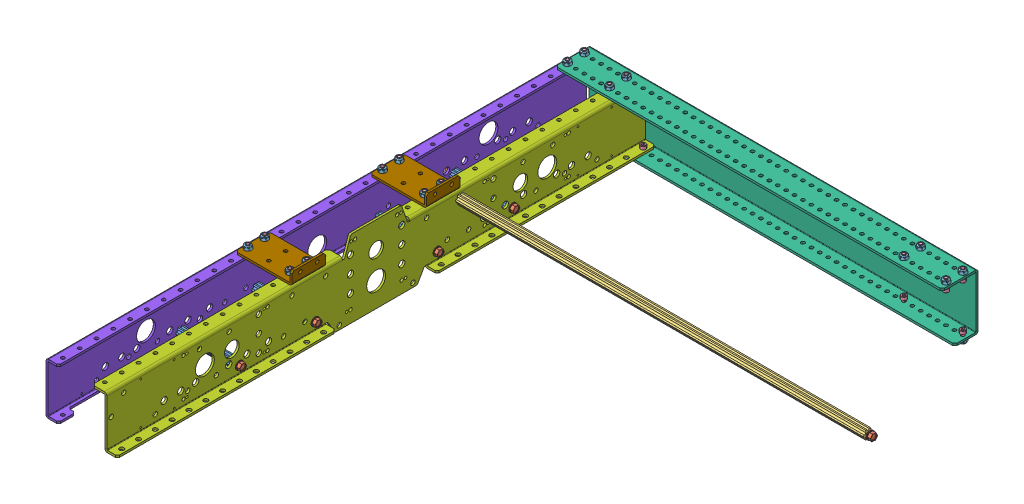
SolidWorks assembly AM14U3 Long Frame Half, configuration Default. Lengths in mm.
Overall size (722.38 116.33 816.74).
60 component instances, 9 part files, 125 mates.
Components (placement in the parent):
- 500 Churro 3.375 in-1: 500 Churro 3.375 in [Default] at (-501.65 -66.929 448.437) x (0 0 1) z (-1 0 0) size (14.66 12.7 85.72)
- 500 Churro 3.375 in-2: 500 Churro 3.375 in [Default] at (-501.65 -66.929 562.737) x (0 0 1) z (-1 0 0) size (14.66 12.7 85.72)
- 500 Churro 3.375 in-3: 500 Churro 3.375 in [Default] at (-501.65 -66.929 264.287) x (0 0 1) z (-1 0 0) size (14.66 12.7 85.72)
- 500 Churro 3.375 in-4: 500 Churro 3.375 in [Default] at (-501.65 -66.929 149.987) x (0 0 1) z (-1 0 0) size (14.66 12.7 85.72)
- 0.25-20 x 0.75 in Thread Rolling Screw-1: 0.25-20 x 0.75 in Thread Rolling Screw [FHTS 0.25-20-G-0.75-C] at (-498.475 -66.929 562.737) x (-1 0 0) z (0 0.924225 0.381849) size (24.64 12.19 12.19)
- 0.25-20 x 0.75 in Thread Rolling Screw-2: 0.25-20 x 0.75 in Thread Rolling Screw [FHTS 0.25-20-G-0.75-C] at (-498.475 -66.929 448.437) x (-1 0 0) z (0 0.924225 0.381849) size (24.64 12.19 12.19)
- 0.25-20 x 0.75 in Thread Rolling Screw-3: 0.25-20 x 0.75 in Thread Rolling Screw [FHTS 0.25-20-G-0.75-C] at (-498.475 -66.929 264.287) x (-1 0 0) z (0 0.924225 0.381849) size (24.64 12.19 12.19)
- 0.25-20 x 0.75 in Thread Rolling Screw-4: 0.25-20 x 0.75 in Thread Rolling Screw [FHTS 0.25-20-G-0.75-C] at (-498.475 -66.929 149.987) x (-1 0 0) z (0 0.924225 0.381849) size (24.64 12.19 12.19)
- 0.25-20 x 0.75 in Thread Rolling Screw-5: 0.25-20 x 0.75 in Thread Rolling Screw [FHTS 0.25-20-G-0.75-C] at (-590.55 -66.929 562.737) size (24.64 12.19 12.19)
- 0.25-20 x 0.75 in Thread Rolling Screw-6: 0.25-20 x 0.75 in Thread Rolling Screw [FHTS 0.25-20-G-0.75-C] at (-590.55 -66.929 448.437) size (24.64 12.19 12.19)
- 0.25-20 x 0.75 in Thread Rolling Screw-7: 0.25-20 x 0.75 in Thread Rolling Screw [FHTS 0.25-20-G-0.75-C] at (-590.55 -66.929 149.987) size (24.64 12.19 12.19)
- 0.25-20 x 0.75 in Thread Rolling Screw-8: 0.25-20 x 0.75 in Thread Rolling Screw [FHTS 0.25-20-G-0.75-C] at (-590.55 -66.929 264.287) size (24.64 12.19 12.19)
- 0.25-20 x 0.75 in Thread Rolling Screw-9: 0.25-20 x 0.75 in Thread Rolling Screw [FHTS 0.25-20-G-0.75-C] at (-501.65 -15.494 229.362) size (24.64 12.19 12.19)
- 0.25-20 x 0.75 in Thread Rolling Screw-10: 0.25-20 x 0.75 in Thread Rolling Screw [FHTS 0.25-20-G-0.75-C] at (120.65 -15.494 229.362) x (-1 0 0) z (0 -0.924225 -0.381849) size (24.64 12.19 12.19)
- 500 Churro 24.25 in-1: 500 Churro 24.25 in [Default] at (117.475 -15.494 229.362) x (0 0 1) z (-1 0 0) size (14.66 12.7 615.95)
- 10-32 x 0.5 in SHCS Screw-27: 10-32 x 0.5 in SHCS Screw [HX-SHCS 0.19-32x1.375x1-C] at (-577.85 -11.43 -11.938) x (0 1 0) z (0 0 1) size (17.53 7.94 7.94)
- 10-32 x 0.5 in SHCS Screw-28: 10-32 x 0.5 in SHCS Screw [HX-SHCS 0.19-32x1.375x1-C] at (-577.85 -11.43 -37.338) x (0 1 0) z (0 0 1) size (17.53 7.94 7.94)
- 10-32 x 0.5 in SHCS Screw-29: 10-32 x 0.5 in SHCS Screw [HX-SHCS 0.19-32x1.375x1-C] at (-514.35 -11.43 -37.338) x (0 1 0) z (0 0 1) size (17.53 7.94 7.94)
- 10-32 x 0.5 in SHCS Screw-30: 10-32 x 0.5 in SHCS Screw [HX-SHCS 0.19-32x1.375x1-C] at (-514.35 -11.43 -11.938) x (0 1 0) z (0 0 1) size (17.53 7.94 7.94)
- 10-32 x 0.5 in SHCS Screw-31: 10-32 x 0.5 in SHCS Screw [HX-SHCS 0.19-32x1.375x1-C] at (-488.95 -73.152 -37.338) x (0 -1 0) z (0 0 1) size (17.53 7.94 7.94)
- 10-32 x 0.5 in SHCS Screw-32: 10-32 x 0.5 in SHCS Screw [HX-SHCS 0.19-32x1.375x1-C] at (-577.85 -73.152 -37.338) x (0 -1 0) z (0 0 1) size (17.53 7.94 7.94)
- 10-32 x 0.5 in SHCS Screw-40: 10-32 x 0.5 in SHCS Screw [HX-SHCS 0.19-32x1.375x1-C] at (-6.35 -11.176 -11.938) x (0 1 0) z (-0.991845 0 0.127447) size (17.53 7.94 7.94)
- 10-32 x 0.5 in SHCS Screw-41: 10-32 x 0.5 in SHCS Screw [HX-SHCS 0.19-32x1.375x1-C] at (-6.35 -11.176 -37.338) x (0 1 0) z (0.595464 0 0.803382) size (17.53 7.94 7.94)
- 10-32 x 0.5 in SHCS Screw-42: 10-32 x 0.5 in SHCS Screw [HX-SHCS 0.19-32x1.375x1-C] at (-69.85 -11.176 -11.938) x (0 1 0) z (0.578861 0 0.815426) size (17.53 7.94 7.94)
- 10-32 x 0.5 in SHCS Screw-43: 10-32 x 0.5 in SHCS Screw [HX-SHCS 0.19-32x1.375x1-C] at (-69.85 -11.176 -37.338) x (0 1 0) z (0.958905 0 0.283727) size (17.53 7.94 7.94)
- 10-32 x 0.5 in SHCS Screw-44: 10-32 x 0.5 in SHCS Screw [HX-SHCS 0.19-32x1.375x1-C] at (-6.35 -73.406 -37.338) x (0 -1 0) z (-0.989362 0 -0.145473) size (17.53 7.94 7.94)
- 10-32 x 0.5 in SHCS Screw-45: 10-32 x 0.5 in SHCS Screw [HX-SHCS 0.19-32x1.375x1-C] at (-95.25 -73.406 -37.338) x (0 -1 0) z (-0.875347 0 0.483496) size (17.53 7.94 7.94)
- 10-32 Nylock Nut-27: 10-32 Nylock Nut [Default] at (-69.85 0 -11.938) x (1 0 0) z (0 1 0) size (10.18 11.01 7.1)
- 10-32 Nylock Nut-28: 10-32 Nylock Nut [Default] at (-69.85 0 -37.338) x (1 0 0) z (0 1 0) size (10.18 11.01 7.1)
- 10-32 Nylock Nut-29: 10-32 Nylock Nut [Default] at (-6.35 0 -37.338) x (1 0 0) z (0 1 0) size (10.18 11.01 7.1)
- 10-32 Nylock Nut-30: 10-32 Nylock Nut [Default] at (-6.35 0 -11.938) x (1 0 0) z (0 1 0) size (10.18 11.01 7.1)
- 10-32 Nylock Nut-31: 10-32 Nylock Nut [Default] at (-6.35 -84.582 -37.338) x (1 0 0) z (0 -1 0) size (10.18 11.01 7.1)
- 10-32 Nylock Nut-32: 10-32 Nylock Nut [Default] at (-95.25 -84.582 -37.338) x (1 0 0) z (0 -1 0) size (10.18 11.01 7.1)
- 10-32 Nylock Nut-33: 10-32 Nylock Nut [Default] at (-514.35 0 -11.938) x (1 0 0) z (0 1 0) size (10.18 11.01 7.1)
- 10-32 Nylock Nut-34: 10-32 Nylock Nut [Default] at (-514.35 0 -37.338) x (1 0 0) z (0 1 0) size (10.18 11.01 7.1)
- 10-32 Nylock Nut-35: 10-32 Nylock Nut [Default] at (-577.85 0 -37.338) x (1 0 0) z (0 1 0) size (10.18 11.01 7.1)
- 10-32 Nylock Nut-36: 10-32 Nylock Nut [Default] at (-577.85 0 -11.938) x (1 0 0) z (0 1 0) size (10.18 11.01 7.1)
- 10-32 Nylock Nut-37: 10-32 Nylock Nut [Default] at (-488.95 -84.582 -37.338) x (1 0 0) z (0 -1 0) size (10.18 11.01 7.1)
- 10-32 Nylock Nut-38: 10-32 Nylock Nut [Default] at (-577.85 -84.582 -37.338) x (1 0 0) z (0 -1 0) size (10.18 11.01 7.1)
- 10-32 x 0.5 in SHCS Screw-46: 10-32 x 0.5 in SHCS Screw [HX-SHCS 0.19-32x1.375x1-C] at (-577.85 -11.43 445.262) x (0 1 0) z (0 0 1) size (17.53 7.94 7.94)
- 10-32 x 0.5 in SHCS Screw-47: 10-32 x 0.5 in SHCS Screw [HX-SHCS 0.19-32x1.375x1-C] at (-577.85 -11.43 470.662) x (0 1 0) z (0 0 1) size (17.53 7.94 7.94)
- 10-32 x 0.5 in SHCS Screw-48: 10-32 x 0.5 in SHCS Screw [HX-SHCS 0.19-32x1.375x1-C] at (-514.35 -11.43 445.262) x (0 1 0) z (0 0 1) size (17.53 7.94 7.94)
- 10-32 x 0.5 in SHCS Screw-49: 10-32 x 0.5 in SHCS Screw [HX-SHCS 0.19-32x1.375x1-C] at (-514.35 -11.43 470.662) x (0 1 0) z (0 0 1) size (17.53 7.94 7.94)
- 10-32 x 0.5 in SHCS Screw-50: 10-32 x 0.5 in SHCS Screw [HX-SHCS 0.19-32x1.375x1-C] at (-577.85 -11.43 267.462) x (0 1 0) z (0 0 1) size (17.53 7.94 7.94)
- 10-32 x 0.5 in SHCS Screw-51: 10-32 x 0.5 in SHCS Screw [HX-SHCS 0.19-32x1.375x1-C] at (-577.85 -11.43 242.062) x (0 1 0) z (0 0 1) size (17.53 7.94 7.94)
- 10-32 x 0.5 in SHCS Screw-52: 10-32 x 0.5 in SHCS Screw [HX-SHCS 0.19-32x1.375x1-C] at (-514.35 -11.43 242.062) x (0 1 0) z (0 0 1) size (17.53 7.94 7.94)
- 10-32 x 0.5 in SHCS Screw-53: 10-32 x 0.5 in SHCS Screw [HX-SHCS 0.19-32x1.375x1-C] at (-514.35 -11.43 267.462) x (0 1 0) z (0 0 1) size (17.53 7.94 7.94)
- 10-32 Nylock Nut-39: 10-32 Nylock Nut [Default] at (-514.35 -0.254 267.462) x (1 0 0) z (0 1 0) size (10.18 11.01 7.1)
- 10-32 Nylock Nut-40: 10-32 Nylock Nut [Default] at (-514.35 -0.254 242.062) x (1 0 0) z (0 1 0) size (10.18 11.01 7.1)
- 10-32 Nylock Nut-41: 10-32 Nylock Nut [Default] at (-577.85 -0.254 267.462) x (1 0 0) z (0 1 0) size (10.18 11.01 7.1)
- 10-32 Nylock Nut-42: 10-32 Nylock Nut [Default] at (-577.85 -0.254 242.062) x (1 0 0) z (0 1 0) size (10.18 11.01 7.1)
- 10-32 Nylock Nut-43: 10-32 Nylock Nut [Default] at (-514.35 -0.254 470.662) x (1 0 0) z (0 1 0) size (10.18 11.01 7.1)
- 10-32 Nylock Nut-44: 10-32 Nylock Nut [Default] at (-577.85 -0.254 470.662) x (1 0 0) z (0 1 0) size (10.18 11.01 7.1)
- 10-32 Nylock Nut-45: 10-32 Nylock Nut [Default] at (-577.85 -0.254 445.262) x (1 0 0) z (0 1 0) size (10.18 11.01 7.1)
- 10-32 Nylock Nut-46: 10-32 Nylock Nut [Default] at (-514.35 -0.254 445.262) x (1 0 0) z (0 1 0) size (10.18 11.01 7.1)
- AM14U3 End Plate_Long-1: AM14U3 End Plate_Long [Default] at (-488.098 60.9785 -76.8664) x (1 0 0) z (0 -1 0) size (584.2 53.97 84.58)
- AM14U3 Inner Plate-1: AM14U3 Inner Plate [Default] at (-501.65 -77.216 762.762) x (0 0 -1) z (0 -1 0) size (812.8 38.1 116.33)
- AM14U3 Outer Plate-1: AM14U3 Outer Plate [DefaultSM-FLAT-PATTERN] at (-587.375 -77.216 -50.038) x (0 0 1) z (0 -1 0) size (812.8 19.05 77.72)
- Bracket 2x3 Hole Pattern-1: Bracket 2x3 Hole Pattern [Default] at (-584.2 -3.429 496.062) size (85.72 19.05 50.8)
- Bracket 2x3 Hole Pattern-2: Bracket 2x3 Hole Pattern [Default] at (-584.2 -3.429 292.862) size (85.72 19.05 50.8)
Mates (geometry in assembly coordinates):
- Coincident1: coincident aligned: plane of AM14U3 End Plate_Long-1 through (0 0 0) normal (0 0 1); plane of assembly through (0 0 0) normal (0 0 1)
- Coincident2: coincident aligned: plane of AM14U3 End Plate_Long-1 through (0 0 0) normal (0 1 0); plane of assembly through (0 0 0) normal (0 1 0)
- Coincident3: coincident aligned: plane of AM14U3 End Plate_Long-1 through (0 -81.407 -50.8) normal (1 0 0); plane of assembly through (0 0 0) normal (1 0 0)
- Concentric1: concentric anti-aligned: cylinder of AM14U3 End Plate_Long-1 through (-577.85 0 -37.338) axis (0 -1 0) radius 2.667; cylinder of AM14U3 Outer Plate-1 through (-577.85 -81.153 -37.338) axis (0 1 0) radius 2.667
- Concentric2: concentric aligned: cylinder of AM14U3 End Plate_Long-1 through (-577.85 -5.08 -11.938) axis (0 1 0) radius 2.667; cylinder of AM14U3 Outer Plate-1 through (-577.85 -81.153 -11.938) axis (0 1 0) radius 2.667
- Distance1: distance = 0.254 mm anti-aligned: plane of AM14U3 Outer Plate-1 through (-587.375 -3.429 762.762) normal (0 1 0); plane of AM14U3 End Plate_Long-1 through (0 -3.175 0) normal (0 -1 0)
- Concentric4: concentric anti-aligned: cylinder of AM14U3 End Plate_Long-1 through (-514.35 0 -37.338) axis (0 -1 0) radius 2.667; cylinder of AM14U3 Inner Plate-1 through (-514.35 -81.153 -37.338) axis (0 1 0) radius 2.667
- Concentric5: concentric aligned: cylinder of AM14U3 End Plate_Long-1 through (-514.35 -5.08 -11.938) axis (0 1 0) radius 2.667; cylinder of AM14U3 Inner Plate-1 through (-514.35 -81.153 -11.938) axis (0 1 0) radius 2.667
- Distance2: distance = 0.254 mm anti-aligned: plane of AM14U3 Inner Plate-1 through (-501.65 -3.429 -50.038) normal (0 1 0); plane of AM14U3 End Plate_Long-1 through (0 -3.175 0) normal (0 -1 0)
- Concentric312: concentric aligned: cylinder of AM14U3 Inner Plate-1 through (-514.35 -81.153 445.262) axis (0 1 0) radius 2.667; cylinder of Bracket 2x3 Hole Pattern-1 through (-514.35 -3.429 445.262) axis (0 1 0) radius 2.667
- Coincident332: coincident anti-aligned: circle of AM14U3 Inner Plate-1; cylinder of Bracket 2x3 Hole Pattern-1 through (-514.35 -3.429 470.662) axis (0 1 0) radius 2.667
- Coincident333: coincident anti-aligned: plane of AM14U3 Outer Plate-1 through (-587.375 -3.429 762.762) normal (0 1 0); plane of Bracket 2x3 Hole Pattern-1 through (-584.2 -3.429 432.562) normal (0 -1 0)
- Concentric313: concentric aligned: cylinder of AM14U3 Inner Plate-1 through (-514.35 -81.153 267.462) axis (0 1 0) radius 2.667; cylinder of Bracket 2x3 Hole Pattern-2 through (-514.35 -3.429 267.462) axis (0 1 0) radius 2.667
- Concentric314: concentric aligned: cylinder of AM14U3 Inner Plate-1 through (-514.35 -81.153 242.062) axis (0 1 0) radius 2.667; cylinder of Bracket 2x3 Hole Pattern-2 through (-514.35 -3.429 242.062) axis (0 1 0) radius 2.667
- Coincident334: coincident anti-aligned: plane of AM14U3 Inner Plate-1 through (-501.65 -3.429 -50.038) normal (0 1 0); plane of Bracket 2x3 Hole Pattern-2 through (-584.2 -3.429 229.362) normal (0 -1 0)
- Concentric331: concentric anti-aligned: cylinder of AM14U3 Outer Plate-1 through (-571.5 -66.929 448.437) axis (-1 0 0) radius 3.3782; cylinder of 500 Churro 3.375 in-1 through (-587.375 -66.929 448.437) axis (1 0 0) radius 2.9337
- Coincident351: coincident anti-aligned: plane of AM14U3 Outer Plate-1 through (-587.375 -7.366 -50.038) normal (1 0 0); plane of 500 Churro 3.375 in-1 through (-587.375 -63.754 453.9363) normal (-1 0 0)
- Concentric332: concentric anti-aligned: cylinder of AM14U3 Outer Plate-1 through (-571.5 -66.929 264.287) axis (-1 0 0) radius 3.3782; cylinder of 500 Churro 3.375 in-3 through (-587.375 -66.929 264.287) axis (1 0 0) radius 2.9337
- Coincident352: coincident anti-aligned: plane of AM14U3 Outer Plate-1 through (-587.375 -7.366 -50.038) normal (1 0 0); plane of 500 Churro 3.375 in-3 through (-587.375 -63.754 269.7863) normal (-1 0 0)
- Concentric333: concentric anti-aligned: cylinder of AM14U3 Outer Plate-1 through (-571.5 -66.929 149.987) axis (-1 0 0) radius 3.3782; cylinder of 500 Churro 3.375 in-4 through (-587.375 -66.929 149.987) axis (1 0 0) radius 2.9337
- Coincident353: coincident anti-aligned: plane of AM14U3 Outer Plate-1 through (-587.375 -7.366 -50.038) normal (1 0 0); plane of 500 Churro 3.375 in-4 through (-587.375 -63.754 155.4863) normal (-1 0 0)
- Concentric334: concentric anti-aligned: cylinder of AM14U3 Outer Plate-1 through (-571.5 -66.929 562.737) axis (-1 0 0) radius 3.3782; cylinder of 500 Churro 3.375 in-2 through (-587.375 -66.929 562.737) axis (1 0 0) radius 2.9337
- Coincident354: coincident anti-aligned: plane of AM14U3 Outer Plate-1 through (-587.375 -7.366 -50.038) normal (1 0 0); plane of 500 Churro 3.375 in-2 through (-587.375 -63.754 568.2363) normal (-1 0 0)
- Concentric3361: concentric aligned: cylinder of AM14U3 Inner Plate-1 through (-520.7 -66.929 562.737) axis (1 0 0) radius 3.3528; cylinder of 0.25-20 x 0.75 in Thread Rolling Screw-1 through (-498.475 -66.929 562.737) axis (1 0 0) radius 3.175
- Coincident3561: coincident anti-aligned: plane of AM14U3 Inner Plate-1 through (-498.475 -7.366 762.762) normal (1 0 0); plane of 0.25-20 x 0.75 in Thread Rolling Screw-1 through (-498.475 -68.1414 565.6714) normal (-1 0 0)
- Concentric3371: concentric aligned: cylinder of AM14U3 Inner Plate-1 through (-520.7 -66.929 448.437) axis (1 0 0) radius 3.3528; cylinder of 0.25-20 x 0.75 in Thread Rolling Screw-2 through (-498.475 -66.929 448.437) axis (1 0 0) radius 3.175
- Coincident3571: coincident anti-aligned: plane of AM14U3 Inner Plate-1 through (-498.475 -7.366 762.762) normal (1 0 0); plane of 0.25-20 x 0.75 in Thread Rolling Screw-2 through (-498.475 -68.1414 451.3714) normal (-1 0 0)
- Concentric3381: concentric aligned: cylinder of AM14U3 Inner Plate-1 through (-520.7 -66.929 264.287) axis (1 0 0) radius 3.3528; cylinder of 0.25-20 x 0.75 in Thread Rolling Screw-3 through (-498.475 -66.929 264.287) axis (1 0 0) radius 3.175
- Coincident3581: coincident anti-aligned: plane of AM14U3 Inner Plate-1 through (-498.475 -7.366 762.762) normal (1 0 0); plane of 0.25-20 x 0.75 in Thread Rolling Screw-3 through (-498.475 -68.1414 267.2214) normal (-1 0 0)
- Concentric3391: concentric aligned: cylinder of AM14U3 Inner Plate-1 through (-520.7 -66.929 149.987) axis (1 0 0) radius 3.3528; cylinder of 0.25-20 x 0.75 in Thread Rolling Screw-4 through (-498.475 -66.929 149.987) axis (1 0 0) radius 3.175
- Coincident3591: coincident anti-aligned: plane of AM14U3 Inner Plate-1 through (-498.475 -7.366 762.762) normal (1 0 0); plane of 0.25-20 x 0.75 in Thread Rolling Screw-4 through (-498.475 -68.1414 152.9214) normal (-1 0 0)
- Concentric3401: concentric aligned: cylinder of AM14U3 Outer Plate-1 through (-571.5 -66.929 562.737) axis (-1 0 0) radius 3.3782; cylinder of 0.25-20 x 0.75 in Thread Rolling Screw-5 through (-590.55 -66.929 562.737) axis (-1 0 0) radius 3.175
- Coincident3601: coincident anti-aligned: plane of AM14U3 Outer Plate-1 through (-590.55 -7.366 -50.038) normal (-1 0 0); plane of 0.25-20 x 0.75 in Thread Rolling Screw-5 through (-590.55 -63.754 562.737) normal (1 0 0)
- Concentric3411: concentric aligned: cylinder of AM14U3 Outer Plate-1 through (-571.5 -66.929 448.437) axis (-1 0 0) radius 3.3782; cylinder of 0.25-20 x 0.75 in Thread Rolling Screw-6 through (-590.55 -66.929 448.437) axis (-1 0 0) radius 3.175
- Coincident3611: coincident anti-aligned: plane of AM14U3 Outer Plate-1 through (-590.55 -7.366 -50.038) normal (-1 0 0); plane of 0.25-20 x 0.75 in Thread Rolling Screw-6 through (-590.55 -63.754 448.437) normal (1 0 0)
- Concentric3421: concentric aligned: cylinder of AM14U3 Outer Plate-1 through (-571.5 -66.929 149.987) axis (-1 0 0) radius 3.3782; cylinder of 0.25-20 x 0.75 in Thread Rolling Screw-7 through (-590.55 -66.929 149.987) axis (-1 0 0) radius 3.175
- Coincident3621: coincident anti-aligned: plane of AM14U3 Outer Plate-1 through (-590.55 -7.366 -50.038) normal (-1 0 0); plane of 0.25-20 x 0.75 in Thread Rolling Screw-7 through (-590.55 -63.754 149.987) normal (1 0 0)
- Concentric3431: concentric aligned: cylinder of AM14U3 Outer Plate-1 through (-571.5 -66.929 264.287) axis (-1 0 0) radius 3.3782; cylinder of 0.25-20 x 0.75 in Thread Rolling Screw-8 through (-590.55 -66.929 264.287) axis (-1 0 0) radius 3.175
- Coincident3631: coincident anti-aligned: plane of AM14U3 Outer Plate-1 through (-590.55 -7.366 -50.038) normal (-1 0 0); plane of 0.25-20 x 0.75 in Thread Rolling Screw-8 through (-590.55 -63.754 264.287) normal (1 0 0)
- Concentric3441: concentric aligned: cylinder of AM14U3 Inner Plate-1 through (-482.6 -15.494 229.362) axis (-1 0 0) radius 3.3528; cylinder of 0.25-20 x 0.75 in Thread Rolling Screw-9 through (-501.65 -15.494 229.362) axis (-1 0 0) radius 3.175
- Coincident3641: coincident anti-aligned: plane of AM14U3 Inner Plate-1 through (-501.65 -7.366 762.762) normal (-1 0 0); plane of 0.25-20 x 0.75 in Thread Rolling Screw-9 through (-501.65 -12.319 229.362) normal (1 0 0)
- Concentric3442: concentric anti-aligned: cylinder of 0.25-20 x 0.75 in Thread Rolling Screw-9 through (-501.65 -15.494 229.362) axis (-1 0 0) radius 3.175; cylinder of 500 Churro 24.25 in-1 through (-498.475 -15.494 229.362) axis (1 0 0) radius 2.9337
- Coincident3642: coincident anti-aligned: plane of AM14U3 Inner Plate-1 through (-498.475 -7.366 762.762) normal (1 0 0); plane of 500 Churro 24.25 in-1 through (-498.475 -12.319 234.8613) normal (-1 0 0)
- Concentric3443: concentric aligned: cylinder of 0.25-20 x 0.75 in Thread Rolling Screw-10 through (120.65 -15.494 229.362) axis (1 0 0) radius 3.175; cylinder of 500 Churro 24.25 in-1 through (-498.475 -15.494 229.362) axis (1 0 0) radius 2.9337
- Distance11: distance = 3.175 mm anti-aligned: plane of 500 Churro 24.25 in-1 through (117.475 -12.319 234.8613) normal (1 0 0); plane of 0.25-20 x 0.75 in Thread Rolling Screw-10 through (120.65 -14.2816 226.4276) normal (-1 0 0)
- Concentric34441: concentric anti-aligned: cylinder of AM14U3 Outer Plate-1 through (-577.85 -81.153 -11.938) axis (0 1 0) radius 2.667; cylinder of 10-32 x 0.5 in SHCS Screw-27 through (-577.85 -43.18 -11.938) axis (0 -1 0) radius 3.9688
- Coincident36431: coincident anti-aligned: plane of AM14U3 Outer Plate-1 through (-587.375 -6.604 762.762) normal (0 -1 0); plane of 10-32 x 0.5 in SHCS Screw-27 through (-581.8188 -6.604 -11.938) normal (0 1 0)
- Concentric34451: concentric anti-aligned: cylinder of AM14U3 Outer Plate-1 through (-577.85 -81.153 -37.338) axis (0 1 0) radius 2.667; cylinder of 10-32 x 0.5 in SHCS Screw-28 through (-577.85 -43.18 -37.338) axis (0 -1 0) radius 3.9688
- Coincident36441: coincident anti-aligned: plane of AM14U3 Outer Plate-1 through (-587.375 -6.604 762.762) normal (0 -1 0); plane of 10-32 x 0.5 in SHCS Screw-28 through (-581.8188 -6.604 -37.338) normal (0 1 0)
- Concentric34461: concentric anti-aligned: cylinder of AM14U3 Inner Plate-1 through (-514.35 -81.153 -37.338) axis (0 1 0) radius 2.667; cylinder of 10-32 x 0.5 in SHCS Screw-29 through (-514.35 -43.18 -37.338) axis (0 -1 0) radius 3.9688
- Coincident36451: coincident anti-aligned: plane of AM14U3 Inner Plate-1 through (-501.65 -6.604 -50.038) normal (0 -1 0); plane of 10-32 x 0.5 in SHCS Screw-29 through (-518.3188 -6.604 -37.338) normal (0 1 0)
- Concentric34471: concentric anti-aligned: cylinder of AM14U3 Inner Plate-1 through (-514.35 -81.153 -11.938) axis (0 1 0) radius 2.667; cylinder of 10-32 x 0.5 in SHCS Screw-30 through (-514.35 -43.18 -11.938) axis (0 -1 0) radius 3.9688
- Coincident36461: coincident anti-aligned: plane of AM14U3 Inner Plate-1 through (-501.65 -6.604 -50.038) normal (0 -1 0); plane of 10-32 x 0.5 in SHCS Screw-30 through (-518.3188 -6.604 -11.938) normal (0 1 0)
- Concentric34481: concentric aligned: cylinder of AM14U3 Inner Plate-1 through (-488.95 -81.153 -37.338) axis (0 1 0) radius 3.3528; cylinder of 10-32 x 0.5 in SHCS Screw-31 through (-488.95 -41.402 -37.338) axis (0 1 0) radius 3.9688
- Coincident36471: coincident anti-aligned: plane of AM14U3 Inner Plate-1 through (-498.475 -77.978 -50.038) normal (0 1 0); plane of 10-32 x 0.5 in SHCS Screw-31 through (-484.9812 -77.978 -37.338) normal (0 -1 0)
- Concentric34491: concentric aligned: cylinder of AM14U3 Outer Plate-1 through (-577.85 -81.153 -37.338) axis (0 1 0) radius 2.667; cylinder of 10-32 x 0.5 in SHCS Screw-32 through (-577.85 -41.402 -37.338) axis (0 1 0) radius 3.9688
- Coincident36481: coincident anti-aligned: plane of AM14U3 Outer Plate-1 through (-587.375 -77.978 762.762) normal (0 1 0); plane of 10-32 x 0.5 in SHCS Screw-32 through (-573.8813 -77.978 -37.338) normal (0 -1 0)
- Concentric3457: concentric aligned: circle of AM14U3 End Plate_Long-1; cylinder of 10-32 x 0.5 in SHCS Screw-41 through (-6.35 -42.926 -37.338) axis (0 -1 0) radius 2.413
- Concentric3458: concentric anti-aligned: cylinder of AM14U3 End Plate_Long-1 through (-6.35 -5.08 -11.938) axis (0 1 0) radius 2.667; cylinder of 10-32 x 0.5 in SHCS Screw-40 through (-6.35 -42.926 -11.938) axis (0 -1 0) radius 2.413
- Coincident3656: coincident aligned: plane of 10-32 x 0.5 in SHCS Screw-40 through (-6.8558 -6.35 -15.8744) normal (0 1 0); plane of 10-32 x 0.5 in SHCS Screw-41 through (-9.5384 -6.35 -34.9748) normal (0 1 0)
- Concentric3459: concentric aligned: cylinder of AM14U3 End Plate_Long-1 through (-69.85 0 -37.338) axis (0 -1 0) radius 2.667; cylinder of 10-32 x 0.5 in SHCS Screw-43 through (-69.85 -42.926 -37.338) axis (0 -1 0) radius 2.413
- Concentric3460: concentric anti-aligned: cylinder of AM14U3 End Plate_Long-1 through (-69.85 -5.08 -11.938) axis (0 1 0) radius 2.667; cylinder of 10-32 x 0.5 in SHCS Screw-42 through (-69.85 -42.926 -11.938) axis (0 -1 0) radius 2.413
- Coincident3657: coincident aligned: plane of 10-32 x 0.5 in SHCS Screw-42 through (-73.0862 -6.35 -9.6406) normal (0 1 0); plane of 10-32 x 0.5 in SHCS Screw-43 through (-70.976 -6.35 -33.5323) normal (0 1 0)
- Coincident3658: coincident aligned: plane of 10-32 x 0.5 in SHCS Screw-40 through (-6.8558 -6.35 -15.8744) normal (0 1 0); plane of 10-32 x 0.5 in SHCS Screw-42 through (-73.0862 -6.35 -9.6406) normal (0 1 0)
- Distance12: distance = 3.175 mm anti-aligned: plane of AM14U3 End Plate_Long-1 through (0 -3.175 0) normal (0 -1 0); plane of 10-32 x 0.5 in SHCS Screw-42 through (-73.0862 -6.35 -9.6406) normal (0 1 0)
- Concentric3461: concentric anti-aligned: cylinder of AM14U3 End Plate_Long-1 through (-6.35 0 -37.338) axis (0 -1 0) radius 2.667; cylinder of 10-32 x 0.5 in SHCS Screw-44 through (-6.35 -41.656 -37.338) axis (0 1 0) radius 2.413
- Distance13: distance = 3.175 mm anti-aligned: plane of AM14U3 End Plate_Long-1 through (-787.4 -81.407 -19.05) normal (0 1 0); plane of 10-32 x 0.5 in SHCS Screw-44 through (-6.9273 -78.232 -33.4115) normal (0 -1 0)
- Concentric3462: concentric anti-aligned: cylinder of AM14U3 End Plate_Long-1 through (-95.25 0 -37.338) axis (0 -1 0) radius 2.667; cylinder of 10-32 x 0.5 in SHCS Screw-45 through (-95.25 -41.656 -37.338) axis (0 1 0) radius 2.413
- Distance14: distance = 3.175 mm anti-aligned: plane of AM14U3 End Plate_Long-1 through (-787.4 -81.407 -19.05) normal (0 1 0); plane of 10-32 x 0.5 in SHCS Screw-45 through (-93.3311 -78.232 -33.864) normal (0 -1 0)
- Concentric34631: concentric aligned: cylinder of AM14U3 End Plate_Long-1 through (-69.85 -5.08 -11.938) axis (0 1 0) radius 2.667; cylinder of 10-32 Nylock Nut-27 through (-69.85 5.9531 -11.938) axis (0 1 0) radius 2.0193
- Coincident36621: coincident anti-aligned: plane of AM14U3 End Plate_Long-1 through (0 0 0) normal (0 1 0); plane of 10-32 Nylock Nut-27 through (-69.85 0 -11.938) normal (0 -1 0)
- Concentric34641: concentric anti-aligned: cylinder of AM14U3 End Plate_Long-1 through (-69.85 0 -37.338) axis (0 -1 0) radius 2.667; cylinder of 10-32 Nylock Nut-28 through (-69.85 5.9531 -37.338) axis (0 1 0) radius 2.0193
- Coincident36631: coincident anti-aligned: plane of AM14U3 End Plate_Long-1 through (0 0 0) normal (0 1 0); plane of 10-32 Nylock Nut-28 through (-69.85 0 -37.338) normal (0 -1 0)
- Concentric34651: concentric anti-aligned: cylinder of AM14U3 End Plate_Long-1 through (-6.35 0 -37.338) axis (0 -1 0) radius 2.667; cylinder of 10-32 Nylock Nut-29 through (-6.35 5.9531 -37.338) axis (0 1 0) radius 2.0193
- Coincident36641: coincident anti-aligned: plane of AM14U3 End Plate_Long-1 through (0 0 0) normal (0 1 0); plane of 10-32 Nylock Nut-29 through (-6.35 0 -37.338) normal (0 -1 0)
- Concentric34661: concentric aligned: cylinder of AM14U3 End Plate_Long-1 through (-6.35 -5.08 -11.938) axis (0 1 0) radius 2.667; cylinder of 10-32 Nylock Nut-30 through (-6.35 5.9531 -11.938) axis (0 1 0) radius 2.0193
- Coincident36651: coincident anti-aligned: plane of AM14U3 End Plate_Long-1 through (0 0 0) normal (0 1 0); plane of 10-32 Nylock Nut-30 through (-6.35 0 -11.938) normal (0 -1 0)
- Concentric34671: concentric aligned: cylinder of AM14U3 End Plate_Long-1 through (-6.35 0 -37.338) axis (0 -1 0) radius 2.667; cylinder of 10-32 Nylock Nut-31 through (-6.35 -90.5351 -37.338) axis (0 -1 0) radius 2.0193
- Coincident36661: coincident anti-aligned: plane of AM14U3 End Plate_Long-1 through (-787.4 -84.582 -19.05) normal (0 -1 0); plane of 10-32 Nylock Nut-31 through (-6.35 -84.582 -37.338) normal (0 1 0)
- Concentric34681: concentric aligned: cylinder of AM14U3 End Plate_Long-1 through (-95.25 0 -37.338) axis (0 -1 0) radius 2.667; cylinder of 10-32 Nylock Nut-32 through (-95.25 -90.5351 -37.338) axis (0 -1 0) radius 2.0193
- Coincident36671: coincident anti-aligned: plane of AM14U3 End Plate_Long-1 through (-787.4 -84.582 -19.05) normal (0 -1 0); plane of 10-32 Nylock Nut-32 through (-95.25 -84.582 -37.338) normal (0 1 0)
- Concentric34691: concentric aligned: cylinder of AM14U3 End Plate_Long-1 through (-514.35 -5.08 -11.938) axis (0 1 0) radius 2.667; cylinder of 10-32 Nylock Nut-33 through (-514.35 5.9531 -11.938) axis (0 1 0) radius 2.0193
- Coincident36681: coincident anti-aligned: plane of AM14U3 End Plate_Long-1 through (0 0 0) normal (0 1 0); plane of 10-32 Nylock Nut-33 through (-514.35 0 -11.938) normal (0 -1 0)
- Concentric34701: concentric anti-aligned: cylinder of AM14U3 End Plate_Long-1 through (-514.35 0 -37.338) axis (0 -1 0) radius 2.667; cylinder of 10-32 Nylock Nut-34 through (-514.35 5.9531 -37.338) axis (0 1 0) radius 2.0193
- Coincident36691: coincident anti-aligned: plane of AM14U3 End Plate_Long-1 through (0 0 0) normal (0 1 0); plane of 10-32 Nylock Nut-34 through (-514.35 0 -37.338) normal (0 -1 0)
- Concentric34711: concentric anti-aligned: cylinder of AM14U3 End Plate_Long-1 through (-577.85 0 -37.338) axis (0 -1 0) radius 2.667; cylinder of 10-32 Nylock Nut-35 through (-577.85 5.9531 -37.338) axis (0 1 0) radius 2.0193
- Coincident36701: coincident anti-aligned: plane of AM14U3 End Plate_Long-1 through (0 0 0) normal (0 1 0); plane of 10-32 Nylock Nut-35 through (-577.85 0 -37.338) normal (0 -1 0)
- Concentric34721: concentric aligned: cylinder of AM14U3 End Plate_Long-1 through (-577.85 -5.08 -11.938) axis (0 1 0) radius 2.667; cylinder of 10-32 Nylock Nut-36 through (-577.85 5.9531 -11.938) axis (0 1 0) radius 2.0193
- Coincident36711: coincident anti-aligned: plane of AM14U3 End Plate_Long-1 through (0 0 0) normal (0 1 0); plane of 10-32 Nylock Nut-36 through (-577.85 0 -11.938) normal (0 -1 0)
- Concentric34731: concentric aligned: cylinder of AM14U3 End Plate_Long-1 through (-488.95 0 -37.338) axis (0 -1 0) radius 2.667; cylinder of 10-32 Nylock Nut-37 through (-488.95 -90.5351 -37.338) axis (0 -1 0) radius 2.0193
- Coincident36721: coincident anti-aligned: plane of AM14U3 End Plate_Long-1 through (-787.4 -84.582 -19.05) normal (0 -1 0); plane of 10-32 Nylock Nut-37 through (-488.95 -84.582 -37.338) normal (0 1 0)
- Concentric34741: concentric aligned: cylinder of AM14U3 End Plate_Long-1 through (-577.85 0 -37.338) axis (0 -1 0) radius 2.667; cylinder of 10-32 Nylock Nut-38 through (-577.85 -90.5351 -37.338) axis (0 -1 0) radius 2.0193
- Coincident36731: coincident anti-aligned: plane of AM14U3 End Plate_Long-1 through (-787.4 -84.582 -19.05) normal (0 -1 0); plane of 10-32 Nylock Nut-38 through (-577.85 -84.582 -37.338) normal (0 1 0)
- Concentric347421: concentric anti-aligned: cylinder of AM14U3 Outer Plate-1 through (-577.85 -81.153 445.262) axis (0 1 0) radius 2.667; cylinder of 10-32 x 0.5 in SHCS Screw-46 through (-577.85 -43.18 445.262) axis (0 -1 0) radius 3.9688
- Coincident367321: coincident anti-aligned: plane of AM14U3 Outer Plate-1 through (-587.375 -6.604 762.762) normal (0 -1 0); plane of 10-32 x 0.5 in SHCS Screw-46 through (-581.8188 -6.604 445.262) normal (0 1 0)
- Concentric347431: concentric anti-aligned: cylinder of AM14U3 Outer Plate-1 through (-577.85 -81.153 470.662) axis (0 1 0) radius 2.667; cylinder of 10-32 x 0.5 in SHCS Screw-47 through (-577.85 -43.18 470.662) axis (0 -1 0) radius 3.9688
- Coincident367331: coincident anti-aligned: plane of AM14U3 Outer Plate-1 through (-587.375 -6.604 762.762) normal (0 -1 0); plane of 10-32 x 0.5 in SHCS Screw-47 through (-581.8188 -6.604 470.662) normal (0 1 0)
- Concentric347441: concentric anti-aligned: cylinder of AM14U3 Inner Plate-1 through (-514.35 -81.153 445.262) axis (0 1 0) radius 2.667; cylinder of 10-32 x 0.5 in SHCS Screw-48 through (-514.35 -43.18 445.262) axis (0 -1 0) radius 3.9688
- Coincident367341: coincident anti-aligned: plane of AM14U3 Inner Plate-1 through (-501.65 -6.604 -50.038) normal (0 -1 0); plane of 10-32 x 0.5 in SHCS Screw-48 through (-518.3188 -6.604 445.262) normal (0 1 0)
- Concentric347451: concentric anti-aligned: cylinder of AM14U3 Inner Plate-1 through (-514.35 -81.153 470.662) axis (0 1 0) radius 2.667; cylinder of 10-32 x 0.5 in SHCS Screw-49 through (-514.35 -43.18 470.662) axis (0 -1 0) radius 3.9688
- Coincident367351: coincident anti-aligned: plane of AM14U3 Inner Plate-1 through (-501.65 -6.604 -50.038) normal (0 -1 0); plane of 10-32 x 0.5 in SHCS Screw-49 through (-518.3188 -6.604 470.662) normal (0 1 0)
- Concentric347461: concentric anti-aligned: cylinder of AM14U3 Outer Plate-1 through (-577.85 -81.153 267.462) axis (0 1 0) radius 2.667; cylinder of 10-32 x 0.5 in SHCS Screw-50 through (-577.85 -43.18 267.462) axis (0 -1 0) radius 3.9688
- Coincident367361: coincident anti-aligned: plane of AM14U3 Outer Plate-1 through (-587.375 -6.604 762.762) normal (0 -1 0); plane of 10-32 x 0.5 in SHCS Screw-50 through (-581.8188 -6.604 267.462) normal (0 1 0)
- Concentric347471: concentric anti-aligned: cylinder of AM14U3 Outer Plate-1 through (-577.85 -81.153 242.062) axis (0 1 0) radius 2.667; cylinder of 10-32 x 0.5 in SHCS Screw-51 through (-577.85 -43.18 242.062) axis (0 -1 0) radius 3.9688
- Coincident367371: coincident anti-aligned: plane of AM14U3 Outer Plate-1 through (-587.375 -6.604 762.762) normal (0 -1 0); plane of 10-32 x 0.5 in SHCS Screw-51 through (-581.8188 -6.604 242.062) normal (0 1 0)
- Concentric347481: concentric anti-aligned: cylinder of AM14U3 Inner Plate-1 through (-514.35 -81.153 242.062) axis (0 1 0) radius 2.667; cylinder of 10-32 x 0.5 in SHCS Screw-52 through (-514.35 -43.18 242.062) axis (0 -1 0) radius 3.9688
- Coincident367381: coincident anti-aligned: plane of AM14U3 Inner Plate-1 through (-501.65 -6.604 -50.038) normal (0 -1 0); plane of 10-32 x 0.5 in SHCS Screw-52 through (-518.3188 -6.604 242.062) normal (0 1 0)
- Concentric347491: concentric anti-aligned: cylinder of AM14U3 Inner Plate-1 through (-514.35 -81.153 267.462) axis (0 1 0) radius 2.667; cylinder of 10-32 x 0.5 in SHCS Screw-53 through (-514.35 -43.18 267.462) axis (0 -1 0) radius 3.9688
- Coincident367391: coincident anti-aligned: plane of AM14U3 Inner Plate-1 through (-501.65 -6.604 -50.038) normal (0 -1 0); plane of 10-32 x 0.5 in SHCS Screw-53 through (-518.3188 -6.604 267.462) normal (0 1 0)
- Concentric347501: concentric aligned: cylinder of Bracket 2x3 Hole Pattern-2 through (-514.35 -3.429 267.462) axis (0 1 0) radius 2.667; cylinder of 10-32 Nylock Nut-39 through (-514.35 5.6991 267.462) axis (0 1 0) radius 2.0193
- Coincident367401: coincident anti-aligned: plane of Bracket 2x3 Hole Pattern-2 through (-584.2 -0.254 229.362) normal (0 1 0); plane of 10-32 Nylock Nut-39 through (-514.35 -0.254 267.462) normal (0 -1 0)
- Concentric347511: concentric aligned: cylinder of Bracket 2x3 Hole Pattern-2 through (-514.35 -3.429 242.062) axis (0 1 0) radius 2.667; cylinder of 10-32 Nylock Nut-40 through (-514.35 5.6991 242.062) axis (0 1 0) radius 2.0193
- Coincident367411: coincident anti-aligned: plane of Bracket 2x3 Hole Pattern-2 through (-584.2 -0.254 229.362) normal (0 1 0); plane of 10-32 Nylock Nut-40 through (-514.35 -0.254 242.062) normal (0 -1 0)
- Concentric347521: concentric aligned: cylinder of Bracket 2x3 Hole Pattern-2 through (-577.85 -3.429 267.462) axis (0 1 0) radius 2.667; cylinder of 10-32 Nylock Nut-41 through (-577.85 5.6991 267.462) axis (0 1 0) radius 2.0193
- Coincident367421: coincident anti-aligned: plane of Bracket 2x3 Hole Pattern-2 through (-584.2 -0.254 229.362) normal (0 1 0); plane of 10-32 Nylock Nut-41 through (-577.85 -0.254 267.462) normal (0 -1 0)
- Concentric347531: concentric aligned: cylinder of Bracket 2x3 Hole Pattern-2 through (-577.85 -3.429 242.062) axis (0 1 0) radius 2.667; cylinder of 10-32 Nylock Nut-42 through (-577.85 5.6991 242.062) axis (0 1 0) radius 2.0193
- Coincident367431: coincident anti-aligned: plane of Bracket 2x3 Hole Pattern-2 through (-584.2 -0.254 229.362) normal (0 1 0); plane of 10-32 Nylock Nut-42 through (-577.85 -0.254 242.062) normal (0 -1 0)
- Concentric347541: concentric aligned: cylinder of Bracket 2x3 Hole Pattern-1 through (-514.35 -3.429 470.662) axis (0 1 0) radius 2.667; cylinder of 10-32 Nylock Nut-43 through (-514.35 5.6991 470.662) axis (0 1 0) radius 2.0193
- Coincident367441: coincident anti-aligned: plane of Bracket 2x3 Hole Pattern-1 through (-584.2 -0.254 432.562) normal (0 1 0); plane of 10-32 Nylock Nut-43 through (-514.35 -0.254 470.662) normal (0 -1 0)
- Concentric347551: concentric aligned: cylinder of Bracket 2x3 Hole Pattern-1 through (-577.85 -3.429 470.662) axis (0 1 0) radius 2.667; cylinder of 10-32 Nylock Nut-44 through (-577.85 5.6991 470.662) axis (0 1 0) radius 2.0193
- Coincident367451: coincident anti-aligned: plane of Bracket 2x3 Hole Pattern-1 through (-584.2 -0.254 432.562) normal (0 1 0); plane of 10-32 Nylock Nut-44 through (-577.85 -0.254 470.662) normal (0 -1 0)
- Concentric347561: concentric aligned: cylinder of Bracket 2x3 Hole Pattern-1 through (-577.85 -3.429 445.262) axis (0 1 0) radius 2.667; cylinder of 10-32 Nylock Nut-45 through (-577.85 5.6991 445.262) axis (0 1 0) radius 2.0193
- Coincident367461: coincident anti-aligned: plane of Bracket 2x3 Hole Pattern-1 through (-584.2 -0.254 432.562) normal (0 1 0); plane of 10-32 Nylock Nut-45 through (-577.85 -0.254 445.262) normal (0 -1 0)
- Concentric347571: concentric aligned: cylinder of Bracket 2x3 Hole Pattern-1 through (-514.35 -3.429 445.262) axis (0 1 0) radius 2.667; cylinder of 10-32 Nylock Nut-46 through (-514.35 5.6991 445.262) axis (0 1 0) radius 2.0193
- Coincident367471: coincident anti-aligned: plane of Bracket 2x3 Hole Pattern-1 through (-584.2 -0.254 432.562) normal (0 1 0); plane of 10-32 Nylock Nut-46 through (-514.35 -0.254 445.262) normal (0 -1 0)
